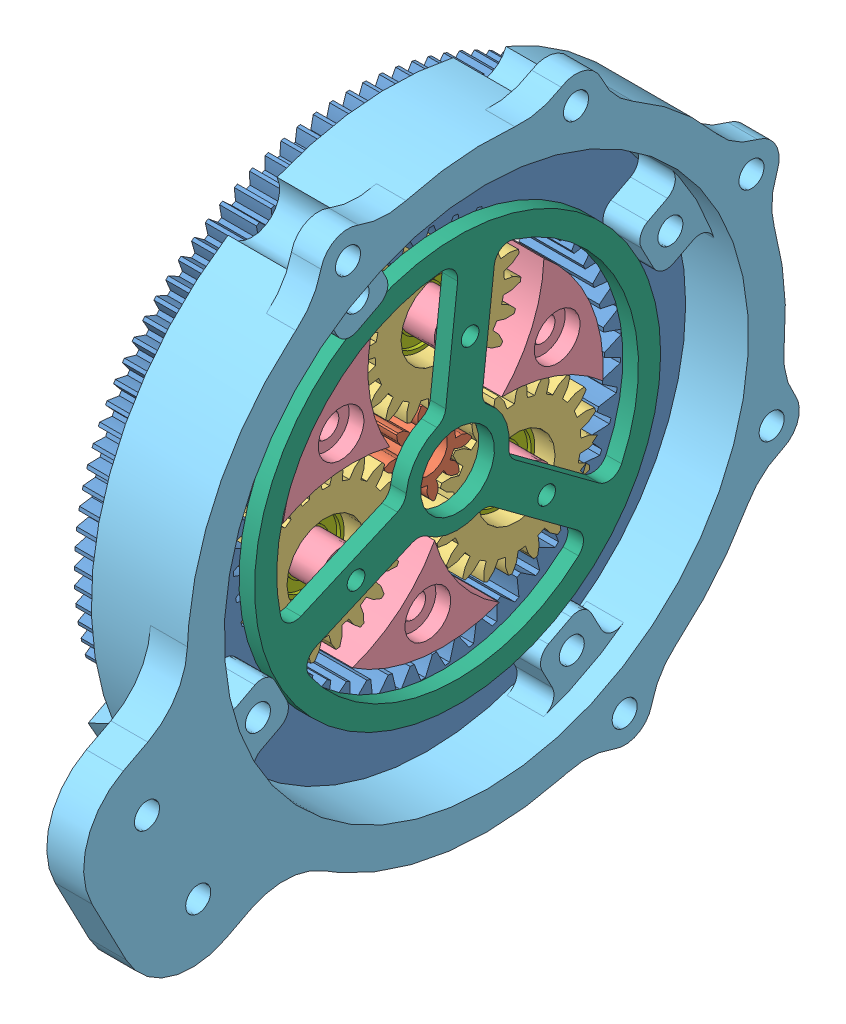
SolidWorks assembly ReductorDeHombroEsnamble, configuration Predeterminado. Lengths in mm.
Overall size (27.9 125.58 131.25).
11 component instances, 7 part files, 20 mates.
Components (placement in the parent):
- AnilloCompatibleEncoder-3: AnilloCompatibleEncoder [Predeterminado] at (29.094 2.7735 0) x (-1 0 0) z (0 0.447786 -0.894141) size (10 72.79 74.49)
- sol-1: sol [ISO - Spur gear 1M 10T 20PA 10FW ---S10A75H50L0.8N] at (24.194 2.7735 0) x (1 0 0) z (0 -0.176004 -0.98439) size (20 11.48 12)
- Planeta-23: Planeta [ISO - Spur gear 1M 20T 20PA 10FW ---S20A75H50L0.8N] at (24.094 17.6774 -1.6953) x (1 0 0) z (0 -0.972388 0.233369) size (10 21.8 21.8)
- Planeta-21: Planeta [ISO - Spur gear 1M 20T 20PA 10FW ---S20A75H50L0.8N] at (34.094 -3.2103 13.7548) x (-1 0 0) z (0 0.30388 -0.95271) size (10 21.8 21.8)
- Planeta-22: Planeta [ISO - Spur gear 1M 20T 20PA 10FW ---S20A75H50L0.8N] at (24.094 -6.1466 -12.0595) x (1 0 0) z (0 0.974016 -0.226479) size (10 21.8 21.8)
- PortaPlanetas-1: PortaPlanetas [Predeterminado] at (19.594 2.7735 0) x (0 -0.113019 -0.993593) z (0 -0.993593 0.113019) size (50.52 16.5 49.09)
- Campana-1: Campana [Predeterminado] at (33.094 2.7735 0) x (0 -0.886589 -0.462559) z (0 -0.462559 0.886589) size (88.5 18 101.87)
- TapaDeportaPlanetas-1: TapaDeportaPlanetas [Predeterminado] at (38.204 2.7735 0) x (0 -0.916986 -0.398919) z (0 0.398919 -0.916986) size (55 2.11 55)
- Rodamiento-1: Rodamiento [Predeterminado] at (31.594 -6.1466 -12.0595) x (0 -0.382646 0.923895) z (0 -0.923895 -0.382646) size (10 3 10)
- Rodamiento-2: Rodamiento [Predeterminado] at (31.594 -3.2103 13.7548) x (0 0.545899 -0.837851) z (0 0.837851 0.545899) size (10 3 10)
- Rodamiento-3: Rodamiento [Predeterminado] at (31.594 17.6774 -1.6953) x (0 0.994511 -0.104628) z (0 0.104628 0.994511) size (10 3 10)
Mates (geometry in assembly coordinates):
- Concéntrica1: concentric: circle of assembly; circle of assembly; circle of AnilloCompatibleEncoder-3; circle of PortaPlanetas-1
- Concéntrica2: concentric: circle of assembly; circle of assembly; circle of Campana-1; circle of TapaDeportaPlanetas-1
- Concéntrica3: concentric: circle of assembly; circle of assembly; circle of PortaPlanetas-1; circle of TapaDeportaPlanetas-1
- Coincidente1: coincident: plane of assembly; plane of assembly; plane of PortaPlanetas-1 through (36.094 -3.2103 13.7548) normal (1 0 0); plane of TapaDeportaPlanetas-1 through (36.094 2.7735 0) normal (-1 0 0)
- Concéntrica4: concentric: circle of assembly; circle of assembly; circle of PortaPlanetas-1; circle of TapaDeportaPlanetas-1
- Coincidente2: coincident: plane of assembly; plane of assembly; plane of Planeta-21 through (24.094 -3.2103 13.7548) normal (-1 0 0); plane of PortaPlanetas-1 through (24.094 2.7735 0) normal (1 0 0)
- Coincidente3: coincident: plane of assembly; plane of assembly; plane of Planeta-23 through (34.094 17.6774 -1.6953) normal (1 0 0); plane of Planeta-21 through (34.094 -3.2103 13.7548) normal (1 0 0)
- Coincidente4: coincident: plane of assembly; plane of assembly; plane of Planeta-21 through (34.094 -3.2103 13.7548) normal (1 0 0); plane of Planeta-22 through (34.094 -6.1466 -12.0595) normal (1 0 0)
- Concéntrica5: concentric: circle of assembly; circle of assembly; circle of Planeta-21; circle of PortaPlanetas-1
- Concéntrica6: concentric: circle of assembly; circle of assembly; circle of Planeta-22; circle of PortaPlanetas-1
- Concéntrica7: concentric: circle of assembly; circle of assembly; circle of Planeta-23; circle of PortaPlanetas-1
- Coincidente6: coincident: plane of assembly; plane of assembly; plane of AnilloCompatibleEncoder-3 through (34.094 -8.3279 21.2781) normal (1 0 0); plane of Planeta-22 through (34.094 -6.1466 -12.0595) normal (1 0 0)
- Coincidente7: coincident: plane of assembly; plane of assembly; plane of AnilloCompatibleEncoder-3 through (34.094 -8.3279 21.2781) normal (1 0 0); plane of Campana-1 through (34.094 2.7735 0) normal (-1 0 0)
- Concéntrica8: concentric: circle of assembly; circle of assembly; circle of Campana-1; circle of AnilloCompatibleEncoder-3
- Concéntrica12: concentric: circle of assembly; circle of assembly; circle of PortaPlanetas-1; circle of Rodamiento-2
- Concéntrica13: concentric: circle of assembly; circle of assembly; circle of PortaPlanetas-1; circle of Rodamiento-1
- Concéntrica16: concentric: circle of assembly; circle of assembly; circle of PortaPlanetas-1; circle of Rodamiento-3
- Ancho1: width: plane of assembly; plane of assembly; plane of assembly; plane of assembly; plane of Rodamiento-3 through (29.094 17.6774 -1.6953) normal (-1 0 0); plane of Rodamiento-3 through (31.094 17.6774 -1.6953) normal (1 0 0); plane of PortaPlanetas-1 through (24.094 2.7735 0) normal (1 0 0); plane of PortaPlanetas-1 through (36.094 -3.2103 13.7548) normal (1 0 0)
- Ancho2: width: plane of assembly; plane of assembly; plane of assembly; plane of assembly; plane of Rodamiento-1 through (29.094 -6.1466 -12.0595) normal (-1 0 0); plane of Rodamiento-1 through (31.094 -6.1466 -12.0595) normal (1 0 0); plane of PortaPlanetas-1 through (24.094 2.7735 0) normal (1 0 0); plane of PortaPlanetas-1 through (36.094 -6.1466 -12.0595) normal (1 0 0)
- Ancho3: width: plane of assembly; plane of assembly; plane of assembly; plane of assembly; plane of Rodamiento-2 through (31.094 -3.2103 13.7548) normal (1 0 0); plane of Rodamiento-2 through (29.094 -3.2103 13.7548) normal (-1 0 0); plane of PortaPlanetas-1 through (24.094 2.7735 0) normal (1 0 0); plane of PortaPlanetas-1 through (36.094 -3.2103 13.7548) normal (1 0 0)
